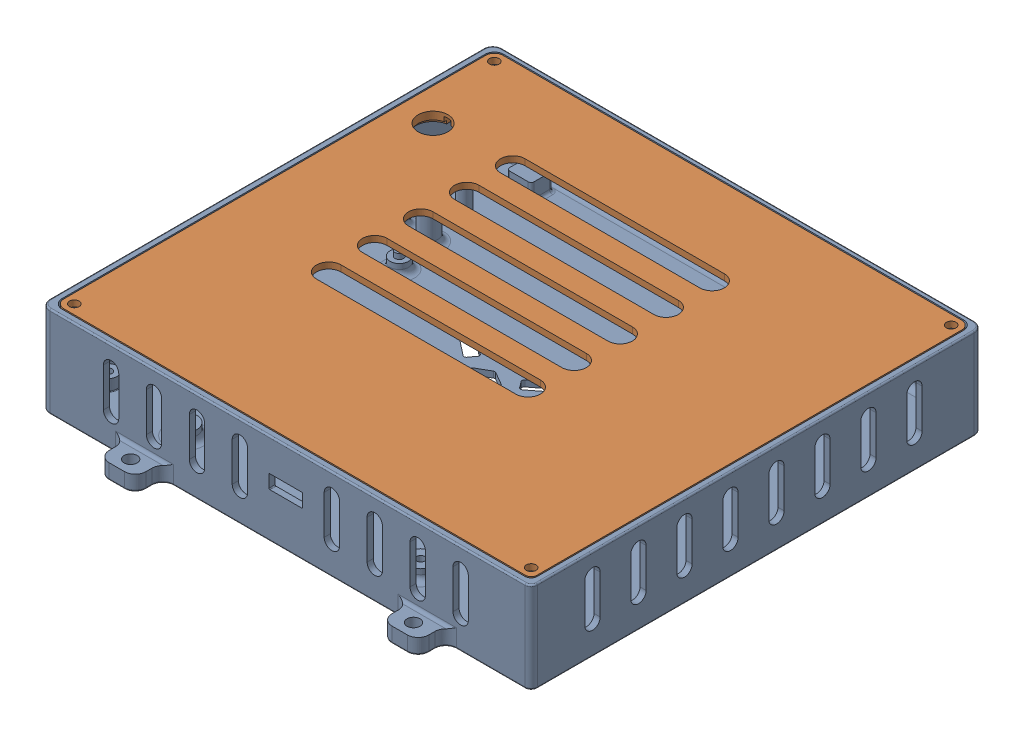
SolidWorks assembly macmini_shell_compact, configuration Default. Lengths in mm.
Overall size (160 29.7 165.5).
2 component instances, 2 part files, 2 mates.
Components (placement in the parent):
- shell_base-1: shell_base [Default] at origin size (160 29.7 165.5)
- shell_cover-1: shell_cover [Default] at (0 27.7 0) size (155.2 3.5 143.2)
Mates (geometry in assembly coordinates):
- Coincident1: coincident anti-aligned: plane of Onboard_Shell-1 through (3 27.7 3) normal (0 1 0); plane of cover_shell-1 through (0 27.7 0) normal (0 -1 0)
- Concentric2: concentric aligned: cylinder of Onboard_Shell-1 through (3.5 12.7 140.5) axis (0 1 0) radius 1.3; cylinder of cover_shell-1 through (3.5 24.7 140.5) axis (0 1 0) radius 1.575
